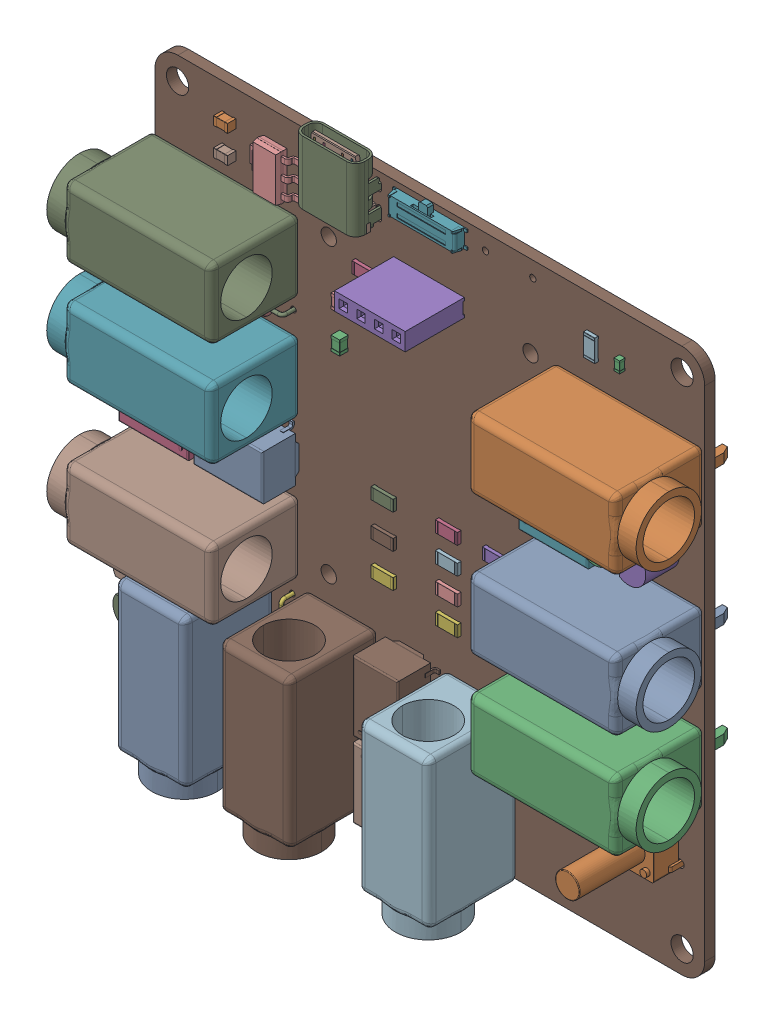
SolidWorks assembly Logic testing(2), configuration Default. Lengths in mm.
Overall size (84.69 83.26 18.9).
46 component instances, 13 part files, 0 mates.
Components (placement in the parent):
- Relay_DPDT_Omron_G6K-2F-1: Relay_DPDT_Omron_G6K-2F [Default] at (-23.44 -1.875 1.595) x (0 1 0) z (0 0 1) size (7.8 10 5.58)
- SW_PUSH_6mm_H13mm-1: SW_PUSH_6mm_H13mm [Default] at (36 -25.375 1.595) x (-1 0 0) z (0 0 1) size (7.17 6 16.5)
- C_0603_1608Metric-1: C_0603_1608Metric [Default] at (27.75 32.875 1.595) x (0 1 0) z (0 0 1) size (1.6 0.8 0.8)
- R_1206_3216Metric-1: R_1206_3216Metric [Default] at (-9 25.875 1.595) size (3.2 1.6 0.55)
- PinSocket_1x04_P2.54mm_Vertical-1: PinSocket_1x04_P2.54mm_Vertical [Default] at (3.775 28.375 1.595) x (0 -1 0) z (0 0 1) size (2.54 10.16 11.6)
- R_1206_3216Metric-2: R_1206_3216Metric [Default] at (9.75 -4.2083 1.595) size (3.2 1.6 0.55)
- 4mm PCB Mount-1: 4mm PCB Mount [Default] at (-29.04 8.125 8.095) x (0 1 0) z (1 0 0) size (10.21 18.8 24)
- 4mm PCB Mount-2: 4mm PCB Mount [Default] at (-29.04 -11.875 8.095) x (0 1 0) z (1 0 0) size (10.21 18.8 24)
- 4mm PCB Mount-3: 4mm PCB Mount [Default] at (-29.04 23.125 8.095) x (0 1 0) z (1 0 0) size (10.21 18.8 24)
- SOT-223-1: SOT-223 [Default] at (-22 32.375 1.595) x (-1 0 0) z (0 0 1) size (7 6.5 1.7)
- R_1206_3216Metric-3: R_1206_3216Metric [Default] at (-6.25 -5.75 1.595) x (-1 0 0) z (0 0 1) size (3.2 1.6 0.55)
- R_1206_3216Metric-4: R_1206_3216Metric [Default] at (23.5 32.875 1.595) x (0 1 0) z (0 0 1) size (3.2 1.6 0.55)
- 4mm PCB Mount-4: 4mm PCB Mount [Default] at (29 3.375 8.095) x (0 -1 0) z (-1 0 0) size (10.21 18.8 24)
- 4mm PCB Mount-5: 4mm PCB Mount [Default] at (29 23.375 8.095) x (0 -1 0) z (-1 0 0) size (10.21 18.8 24)
- 4mm PCB Mount-6: 4mm PCB Mount [Default] at (29 -11.625 8.095) x (0 -1 0) z (-1 0 0) size (10.21 18.8 24)
- R_1206_3216Metric-5: R_1206_3216Metric [Default] at (9.75 -8.0417 1.595) size (3.2 1.6 0.55)
- TO-92_Inline-1: TO-92_Inline [Default] at (36 16.625 1.595) x (0 -1 0) z (0 0 1) size (4.83 3.75 9.8)
- R_1206_3216Metric-6: R_1206_3216Metric [Default] at (3 -11.875 1.595) size (3.2 1.6 0.55)
- SW_SP3T_PCM13-1: SW_SP3T_PCM13 [Default] at (0.25 36.745 1.595) x (-1 0 0) z (0 0 1) size (10.65 4.65 2)
- TO-92_Inline-2: TO-92_Inline [Default] at (-37.02 -21.485 1.595) size (4.83 3.75 9.8)
- USB_C_Receptacle_GCT_USB4085-1: USB_C_Receptacle_GCT_USB4085 [Default] at (-8.625 32.95 1.595) x (-1 0 0) z (0 0 1) size (8.94 9.17 5.56)
- Relay_DPDT_Omron_G6K-2F-2: Relay_DPDT_Omron_G6K-2F [Default] at (23.25 13.375 1.595) x (0 1 0) z (0 0 1) size (7.8 10 5.58)
- Relay_DPDT_Omron_G6K-2F-3: Relay_DPDT_Omron_G6K-2F [Default] at (-2.25 -33.275 1.595) size (7.8 10 5.58)
- D_DO-35_SOD27_P7.62mm_Horizontal-1: D_DO-35_SOD27_P7.62mm_Horizontal [Default] at (-27.21 15.775 1.595) size (8.12 2.02 5.01)
- Relay_DPDT_Omron_G6K-2F-4: Relay_DPDT_Omron_G6K-2F [Default] at (-2.25 -22.465 1.595) x (-1 0 0) z (0 0 1) size (7.8 10 5.58)
- R_1206_3216Metric-7: R_1206_3216Metric [Default] at (3 -4.2083 1.595) x (-1 0 0) z (0 0 1) size (3.2 1.6 0.55)
- D_DO-35_SOD27_P7.62mm_Horizontal-2: D_DO-35_SOD27_P7.62mm_Horizontal [Default] at (-19.75 -29.775 1.595) x (0 -1 0) z (0 0 1) size (8.12 2.02 5.01)
- TO-92_Inline-3: TO-92_Inline [Default] at (31 16.645 1.595) x (0 -1 0) z (0 0 1) size (4.83 3.75 9.8)
- Relay_DPDT_Omron_G6K-2F-5: Relay_DPDT_Omron_G6K-2F [Default] at (-34.19 -1.875 1.595) x (0 -1 0) z (0 0 1) size (7.8 10 5.58)
- R_1206_3216Metric-8: R_1206_3216Metric [Default] at (9.75 -0.375 1.595) size (3.2 1.6 0.55)
- R_1206_3216Metric-9: R_1206_3216Metric [Default] at (-6.25 -10.625 1.595) x (-1 0 0) z (0 0 1) size (3.2 1.6 0.55)
- D_DO-35_SOD27_P7.62mm_Horizontal-3: D_DO-35_SOD27_P7.62mm_Horizontal [Default] at (-29.46 15.775 1.595) x (-1 0 0) z (0 0 1) size (8.12 2.02 5.01)
- R_1206_3216Metric-10: R_1206_3216Metric [Default] at (-6.25 -0.875 1.595) x (-1 0 0) z (0 0 1) size (3.2 1.6 0.55)
- R_1206_3216Metric-11: R_1206_3216Metric [Default] at (3 -8.0417 1.595) size (3.2 1.6 0.55)
- 4mm PCB Mount-7: 4mm PCB Mount [Default] at (-12.25 -28.375 8.095) x (-1 0 0) z (0 1 0) size (10.21 18.8 24)
- 4mm PCB Mount-8: 4mm PCB Mount [Default] at (7.75 -28.375 8.095) x (-1 0 0) z (0 1 0) size (10.21 18.8 24)
- 4mm PCB Mount-9: 4mm PCB Mount [Default] at (-27.25 -28.375 8.095) x (-1 0 0) z (0 1 0) size (10.21 18.8 24)
- C_0805_2012Metric-1: C_0805_2012Metric [Default] at (-28.75 34.875 1.595) x (-1 0 0) z (0 0 1) size (2 1.25 1.25)
- C_0805_2012Metric-2: C_0805_2012Metric [Default] at (-12.25 15.625 1.595) x (0 1 0) z (0 0 1) size (2 1.25 1.25)
- R_1206_3216Metric-12: R_1206_3216Metric [Default] at (3 -0.375 1.595) x (-1 0 0) z (0 0 1) size (3.2 1.6 0.55)
- R_1206_3216Metric-13: R_1206_3216Metric [Default] at (9.75 -11.875 1.595) size (3.2 1.6 0.55)
- D_DO-35_SOD27_P7.62mm_Horizontal-4: D_DO-35_SOD27_P7.62mm_Horizontal [Default] at (-19.75 -27.275 1.595) x (0 1 0) z (0 0 1) size (8.12 2.02 5.01)
- C_0805_2012Metric-3: C_0805_2012Metric [Default] at (-28.75 30.875 1.595) x (-1 0 0) z (0 0 1) size (2 1.25 1.25)
- TO-92_Inline-4: TO-92_Inline [Default] at (-34.48 -26.375 1.595) x (-1 0 0) z (0 0 1) size (4.83 3.75 9.8)
- C_0805_2012Metric-4: C_0805_2012Metric [Default] at (-12.25 20.875 1.595) x (0 -1 0) z (0 0 1) size (2 1.25 1.25)
- Logic testing_PCB-1: Logic testing_PCB [Default] at origin size (79 78.25 1.51)
